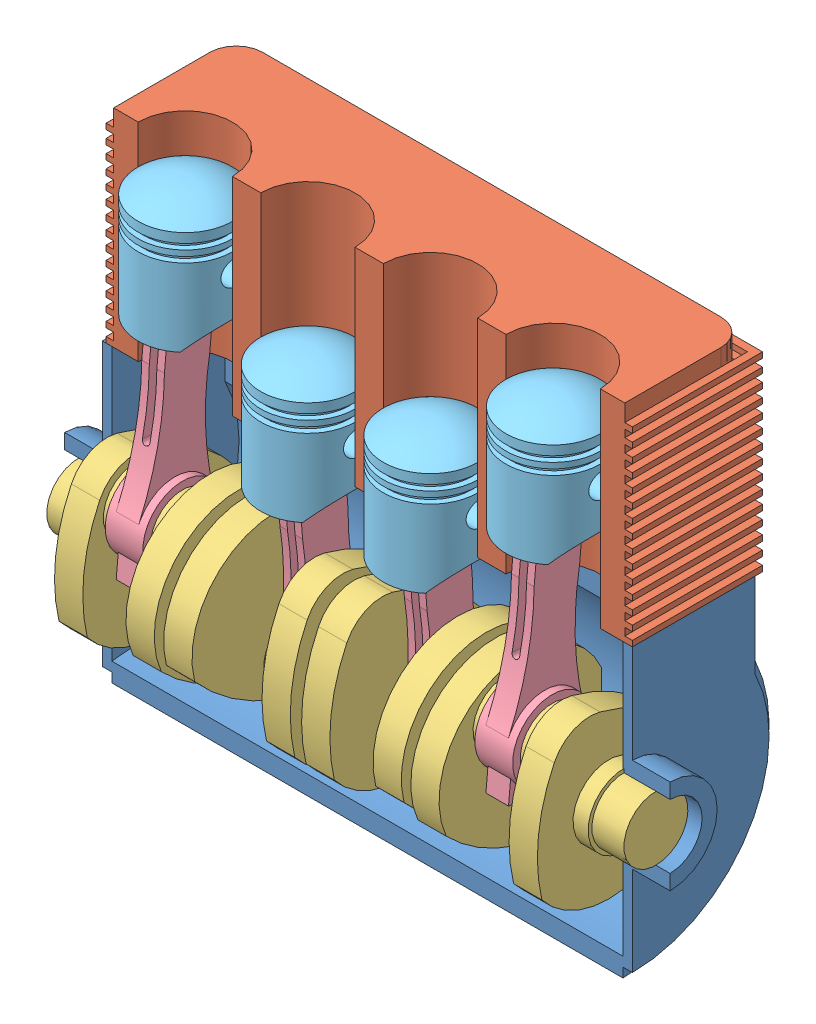
SolidWorks assembly Montaj1, configuration Varsayılan. Lengths in mm.
Overall size (321 264.5 137.14).
11 component instances, 5 part files, 21 mates.
Components (placement in the parent):
- Lower_Block-1: Lower_Block [Varsayılan] at (-156.4221 2.3705 359.75) size (321 154.5 77.5)
- LowerBlock-1: LowerBlock [Varsayılan] at (20.1038 79.3705 380.1731) size (279 110 69)
- Crankshaft-1: Crankshaft [Varsayılan] at (132.0779 2.3705 359.75) x (0 0.399867 -0.916573) z (1 0 0) size (90 92 306)
- Connecting_Rod-1: Connecting_Rod [Varsayılan] at (-93.9221 144.7814 358.7661) x (0 -0.091505 -0.995805) z (1 0 0) size (42 167.05 20)
- Connecting_Rod-2: Connecting_Rod [Varsayılan] at (-28.9221 99.1172 358.7661) x (0 0.075107 -0.997176) z (1 0 0) size (42 167.05 20)
- Connecting_Rod-3: Connecting_Rod [Varsayılan] at (37.0779 99.1172 358.7661) x (0 0.075107 -0.997176) z (1 0 0) size (42 167.05 20)
- Connecting_Rod-4: Connecting_Rod [Varsayılan] at (102.0779 144.7814 358.7661) x (0 -0.091505 -0.995805) z (1 0 0) size (42 167.05 20)
- upperblock-1: upperblock [Varsayılan] at (-92.4221 126.6259 368.0764) x (0 0 -1) z (1 0 0) size (50 64.67 50)
- upperblock-2: upperblock [Varsayılan] at (-27.4221 80.9617 368.0764) x (0 0 -1) z (1 0 0) size (50 64.67 50)
- upperblock-3: upperblock [Varsayılan] at (37.5779 80.9617 368.0764) x (0 0 -1) z (1 0 0) size (50 64.67 50)
- upperblock-4: upperblock [Varsayılan] at (102.5779 126.6259 368.0764) x (0 0 -1) z (1 0 0) size (50 64.67 50)
Mates (geometry in assembly coordinates):
- Çakışık1: coincident: plane of Lower_Block-1 through (-131.4221 79.3705 359.75) normal (0 1 0); plane of LowerBlock-1 through (20.1038 79.3705 380.1731) normal (0 -1 0)
- Çakışık3: coincident: line of Lower_Block-1 through (139.5779 79.3705 359.75) axis (1 0 0); line of LowerBlock-1 through (127.5779 79.3705 359.75) axis (1 0 0)
- Çakışık4: coincident: plane of Lower_Block-1 through (144.5779 2.3705 359.75) normal (1 0 0); plane of LowerBlock-1 through (144.5779 82.3705 359.75) normal (1 0 0)
- Eş Merkezli1: concentric: cylinder of Lower_Block-1 through (144.5779 2.3705 359.75) axis (1 0 0) radius 17; cylinder of Crankshaft-1 through (157.0779 2.3705 359.75) axis (-1 0 0) radius 17
- Genişlik1: width: plane of Lower_Block-1 through (164.5779 2.3705 359.75) normal (1 0 0); plane of Lower_Block-1 through (-156.4221 2.3705 359.75) normal (-1 0 0); plane of Crankshaft-1 through (-148.9221 2.3705 359.75) normal (-1 0 0); plane of Crankshaft-1 through (157.0779 2.3705 359.75) normal (1 0 0)
- Eş Merkezli2: concentric: cylinder of Crankshaft-1 through (-78.9221 13.4982 382.1369) axis (-1 0 0) radius 17; cylinder of Connecting_Rod-1 through (-83.9221 13.4982 382.1369) axis (-1 0 0) radius 16
- Genişlik2: width: plane of Crankshaft-1 through (-108.9221 -17.7374 367.4882) normal (1 0 0); plane of Crankshaft-1 through (-78.9221 21.4406 354.0966) normal (-1 0 0); plane of Connecting_Rod-1 through (-83.9221 131.2004 358.7661) normal (1 0 0); plane of Connecting_Rod-1 through (-103.9221 131.2004 358.7661) normal (-1 0 0)
- Eş Merkezli3: concentric: cylinder of Crankshaft-1 through (-13.9221 -8.7572 337.3631) axis (-1 0 0) radius 17; cylinder of Connecting_Rod-2 through (-18.9221 -8.7572 337.3631) axis (-1 0 0) radius 16
- Genişlik3: width: plane of Crankshaft-1 through (-13.9221 21.9768 348.695) normal (-1 0 0); plane of Crankshaft-1 through (-43.9221 36.4163 364.5864) normal (1 0 0); plane of Connecting_Rod-2 through (-18.9221 109.3187 358.7661) normal (1 0 0); plane of Connecting_Rod-2 through (-38.9221 109.3187 358.7661) normal (-1 0 0)
- Eş Merkezli4: concentric: cylinder of Crankshaft-1 through (22.0779 -8.7572 337.3631) axis (1 0 0) radius 17; cylinder of Connecting_Rod-3 through (47.0779 -8.7572 337.3631) axis (-1 0 0) radius 16
- Genişlik4: width: plane of Crankshaft-1 through (22.0779 21.9768 348.695) normal (1 0 0); plane of Crankshaft-1 through (52.0779 36.4163 364.5864) normal (-1 0 0); plane of Connecting_Rod-3 through (27.0779 109.3187 358.7661) normal (-1 0 0); plane of Connecting_Rod-3 through (47.0779 109.3187 358.7661) normal (1 0 0)
- Eş Merkezli5: concentric: cylinder of Crankshaft-1 through (87.0779 13.4982 382.1369) axis (1 0 0) radius 17; cylinder of Connecting_Rod-4 through (112.0779 13.4982 382.1369) axis (-1 0 0) radius 16
- Genişlik5: width: plane of Crankshaft-1 through (87.0779 21.4406 354.0966) normal (1 0 0); plane of Crankshaft-1 through (117.0779 -17.7374 367.4882) normal (-1 0 0); plane of Connecting_Rod-4 through (92.0779 131.2004 358.7661) normal (-1 0 0); plane of Connecting_Rod-4 through (112.0779 131.2004 358.7661) normal (1 0 0)
- Eş Merkezli10: concentric: cylinder of LowerBlock-1 through (-92.4221 79.3705 359.75) axis (0 1 0) radius 25; cylinder of upperblock-1 through (-92.4221 163.1883 359.75) axis (0 1 0) radius 25
- Eş Merkezli11: concentric: cylinder of Connecting_Rod-1 through (-83.9221 131.2004 358.7661) axis (-1 0 0) radius 6.5; cylinder of upperblock-1 through (-67.4221 131.2004 358.7661) axis (-1 0 0) radius 6.5
- Eş Merkezli12: concentric: cylinder of LowerBlock-1 through (-27.4221 79.3705 359.75) axis (0 1 0) radius 25; cylinder of upperblock-2 through (-27.4221 141.3066 359.75) axis (0 1 0) radius 25
- Eş Merkezli13: concentric: cylinder of Connecting_Rod-2 through (-18.9221 109.3187 358.7661) axis (-1 0 0) radius 6.5; cylinder of upperblock-2 through (-2.4221 109.3187 358.7661) axis (-1 0 0) radius 6.5
- Eş Merkezli14: concentric: cylinder of LowerBlock-1 through (37.5779 79.3705 359.75) axis (0 1 0) radius 25; cylinder of upperblock-3 through (37.5779 141.3066 359.75) axis (0 1 0) radius 25
- Eş Merkezli15: concentric: cylinder of Connecting_Rod-3 through (47.0779 109.3187 358.7661) axis (-1 0 0) radius 6.5; cylinder of upperblock-3 through (62.5779 109.3187 358.7661) axis (-1 0 0) radius 6.5
- Eş Merkezli16: concentric: cylinder of LowerBlock-1 through (102.5779 79.3705 359.75) axis (0 1 0) radius 25; cylinder of upperblock-4 through (102.5779 163.1883 359.75) axis (0 1 0) radius 25
- Eş Merkezli17: concentric: cylinder of Connecting_Rod-4 through (112.0779 131.2004 358.7661) axis (-1 0 0) radius 6.5; cylinder of upperblock-4 through (127.5779 131.2004 358.7661) axis (-1 0 0) radius 6.5
